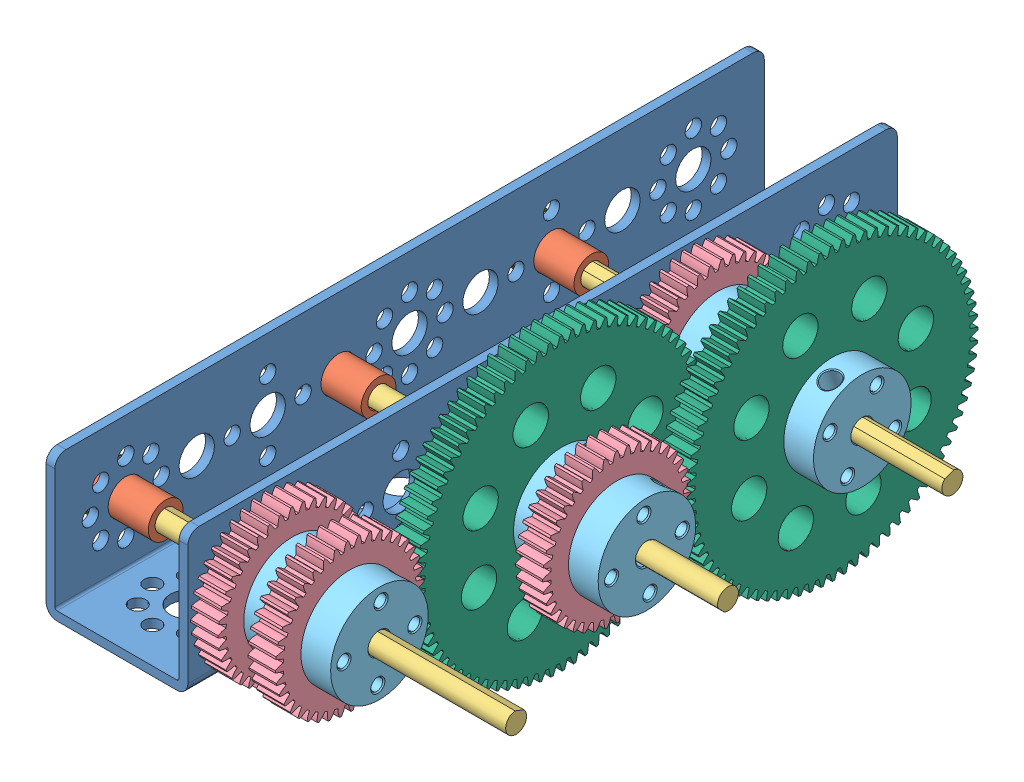
SolidWorks assembly Assem1, configuration Default. Lengths in mm.
Overall size (102.61 86.78 162.15).
25 component instances, 7 part files, 49 mates.
Components (placement in the parent):
- Channel 160mm-1: Channel 160mm [Default] at (26.3428 72.2458 137.2019) size (32 32 160)
- Axle bronze bushing-1: Axle bronze bushing [Default] at (43.7428 88.2458 201.2019) x (0 -0.917806 -0.397029) z (1 0 0) size (11 11 12.4)
- Axle bronze bushing-2: Axle bronze bushing [Default] at (8.9428 88.2458 201.2019) x (0 -0.94918 0.314732) z (-1 0 0) size (11 11 12.4)
- Axle D-shaft-1: Axle D-shaft [Default] at (50.3707 88.2458 201.2019) x (0 -0.370193 -0.928955) z (1 0 0) size (4.73 4.46 100)
- Gear Metric 40T-1: Gear Metric 40T [PreviewCfg] at (43.7428 88.2458 201.2019) x (1 0 0) z (0 -0.086492 0.996253) size (6.2 33.53 33.53)
- Hub axle shaft-1: Hub axle shaft [Default] at (49.9428 88.2458 201.2019) x (0 -0.086492 0.996253) z (-1 0 0) size (22 22 9.5)
- Hub axle shaft-2: Hub axle shaft [Default] at (62.8428 88.2458 201.2019) x (0 0.046409 0.998923) z (-1 0 0) size (22 22 9.5)
- Gear Metric 40T-2: Gear Metric 40T [PreviewCfg] at (56.6428 88.2458 201.2019) x (1 0 0) z (0 0.046409 0.998923) size (6.2 33.53 33.53)
- Gear Metric 80T-1: Gear Metric 80T [Metric - Spur gear 0.8M 80T 20PA 6.2FW ---S80N75H50L8.0N] at (69.5428 88.2458 105.2019) x (1 0 0) z (0 -0.91095 0.412516) size (6.2 65.57 65.57)
- Hub axle shaft-3: Hub axle shaft [Default] at (75.7428 88.2458 105.2019) x (0 -0.91095 0.412516) z (-1 0 0) size (22 22 9.5)
- Axle D-shaft-2: Axle D-shaft [Default] at (50.1599 88.2458 153.2019) x (0 0.722846 0.691009) z (1 0 0) size (4.73 4.46 100)
- Axle bronze bushing-3: Axle bronze bushing [Default] at (8.9428 88.2458 153.2019) x (0 0.924225 0.381849) z (-1 0 0) size (11 11 12.4)
- Axle bronze bushing-4: Axle bronze bushing [Default] at (43.7428 88.2458 153.2019) x (0 0 -1) z (1 0 0) size (11 11 12.4)
- Gear Metric 40T-4: Gear Metric 40T [PreviewCfg] at (43.7428 88.2458 105.2019) x (1 0 0) z (0 0.991285 -0.131734) size (6.2 33.53 33.53)
- Hub axle shaft-4: Hub axle shaft [Default] at (49.9428 88.2458 105.2019) x (0 0.991285 -0.131734) z (-1 0 0) size (22 22 9.5)
- Axle bronze bushing-5: Axle bronze bushing [Default] at (8.9428 88.2458 105.2019) x (0 0.940822 0.338902) z (-1 0 0) size (11 11 12.4)
- Axle bronze bushing-6: Axle bronze bushing [Default] at (43.7428 88.2458 105.2019) x (0 0 -1) z (1 0 0) size (11 11 12.4)
- Axle D-shaft-3: Axle D-shaft [Default] at (52.7684 88.2458 105.2019) x (0 -0.33568 0.941976) z (-1 0 0) size (4.73 4.46 100)
- Gear Metric 80T-2: Gear Metric 80T [Metric - Spur gear 0.8M 80T 20PA 6.2FW ---S80N75H50L8.0N] at (56.5747 88.2458 153.2019) x (1 0 0) z (0 -0.353673 0.935369) size (6.2 65.57 65.57)
- Hub axle shaft-5: Hub axle shaft [Default] at (62.7747 88.2458 153.2019) x (0 -0.353673 0.935369) z (-1 0 0) size (22 22 9.5)
- Hub axle shaft-6: Hub axle shaft [Default] at (75.6747 88.3466 153.7028) x (0 -0.086492 0.996253) z (-1 0 0) size (22 22 9.5)
- Gear Metric 40T-5: Gear Metric 40T [PreviewCfg] at (69.4747 88.3466 153.7028) x (1 0 0) z (0 -0.086492 0.996253) size (6.2 33.53 33.53)
- 39092_txm-axlesetcollars.step-1: 39092_txm-axlesetcollars.step [Default] at (6.0645 87.8505 105.0147) x (0 0 -1) z (1 0 0) size (11.66 11 6.2)
- 39092_txm-axlesetcollars.step-2: 39092_txm-axlesetcollars.step [Default] at (3.456 87.8564 153.401) x (0 -0.79241 -0.609989) z (1 0 0) size (11.66 11 6.2)
- 39092_txm-axlesetcollars.step-3: 39092_txm-axlesetcollars.step [Default] at (6.039 87.8505 201.0147) x (0 0 -1) z (1 0 0) size (11.66 11 6.2)
Mates (geometry in assembly coordinates):
- Concentric1: concentric: cylinder of Channel 160mm-1 through (42.3428 88.2458 201.2019) axis (-1 0 0) radius 4; cylinder of Axle bronze bushing-1 through (31.3428 88.2458 201.2019) axis (1 0 0) radius 3.925
- Coincident1: coincident: plane of Channel 160mm-1 through (42.3428 74.7458 217.2019) normal (1 0 0); plane of Axle bronze bushing-1 through (42.3428 88.2458 201.2019) normal (-1 0 0)
- Concentric2: concentric: cylinder of Channel 160mm-1 through (42.3428 88.2458 201.2019) axis (-1 0 0) radius 4; cylinder of Axle bronze bushing-2 through (21.3428 88.2458 201.2019) axis (-1 0 0) radius 3.925
- Coincident2: coincident: plane of Channel 160mm-1 through (10.3428 104.2458 217.2019) normal (-1 0 0); plane of Axle bronze bushing-2 through (10.3428 88.2458 201.2019) normal (1 0 0)
- Concentric3: concentric: cylinder of Axle bronze bushing-2 through (21.3428 88.2458 201.2019) axis (-1 0 0) radius 2.4; cylinder of Axle D-shaft-1 through (0.3707 88.2458 201.2019) axis (1 0 0) radius 2.365
- Coincident3: coincident: plane of Gear Metric 40T-1 through (49.9428 88.2458 201.2019) normal (1 0 0); plane of Hub axle shaft-1 through (49.9428 88.2458 201.2019) normal (-1 0 0)
- Concentric4: concentric: cylinder of Gear Metric 40T-1 through (49.9428 96.2158 201.8938) axis (1 0 0) radius 1.75; cylinder of Hub axle shaft-1 through (49.9428 96.2158 201.8938) axis (-1 0 0) radius 1.3526
- Concentric5: concentric: cylinder of Gear Metric 40T-1 through (93.7429 88.2458 201.2019) axis (-1 0 0) radius 4; cylinder of Hub axle shaft-1 through (56.6428 88.2458 201.2019) axis (-1 0 0) radius 2.3495
- Concentric6: concentric: cylinder of Axle D-shaft-1 through (0.3707 88.2458 201.2019) axis (1 0 0) radius 2.365; cylinder of Hub axle shaft-1 through (56.6428 88.2458 201.2019) axis (-1 0 0) radius 2.3495
- Concentric7: concentric: cylinder of Hub axle shaft-2 through (69.5428 88.2458 201.2019) axis (-1 0 0) radius 2.3495; cylinder of Gear Metric 40T-2 through (106.6429 88.2458 201.2019) axis (-1 0 0) radius 4
- Concentric8: concentric: cylinder of Hub axle shaft-2 through (62.8428 96.2372 200.8306) axis (-1 0 0) radius 1.3526; cylinder of Gear Metric 40T-2 through (62.8428 96.2372 200.8306) axis (1 0 0) radius 1.75
- Coincident4: coincident: plane of Hub axle shaft-2 through (62.8428 88.2458 201.2019) normal (-1 0 0); plane of Gear Metric 40T-2 through (62.8428 88.2458 201.2019) normal (1 0 0)
- Concentric9: concentric: cylinder of Axle D-shaft-1 through (0.3707 88.2458 201.2019) axis (1 0 0) radius 2.365; cylinder of Hub axle shaft-2 through (69.5428 88.2458 201.2019) axis (-1 0 0) radius 2.3495
- Coincident5: coincident: plane of Hub axle shaft-1 through (56.6428 88.2458 201.2019) normal (1 0 0); plane of Gear Metric 40T-2 through (56.6428 88.2458 201.2019) normal (-1 0 0)
- Coincident6: coincident: plane of Axle bronze bushing-1 through (43.7428 88.2458 201.2019) normal (1 0 0); plane of Gear Metric 40T-1 through (43.7428 88.2458 201.2019) normal (-1 0 0)
- Concentric10: concentric: cylinder of Gear Metric 80T-1 through (119.5429 88.2458 105.2019) axis (-1 0 0) radius 4; cylinder of Hub axle shaft-3 through (72.9428 88.2458 105.2019) axis (1 0 0) radius 3.9624
- Concentric11: concentric: cylinder of Gear Metric 80T-1 through (69.5428 91.5459 112.4895) axis (1 0 0) radius 1.75; cylinder of Hub axle shaft-3 through (75.7428 91.5459 112.4895) axis (-1 0 0) radius 1.3526
- Coincident7: coincident: plane of Gear Metric 80T-1 through (75.7428 88.2458 105.2019) normal (1 0 0); plane of Hub axle shaft-3 through (75.7428 88.2458 105.2019) normal (-1 0 0)
- Concentric12: concentric: cylinder of Axle D-shaft-2 through (0.1599 88.2458 153.2019) axis (1 0 0) radius 2.365; cylinder of Axle bronze bushing-3 through (21.3428 88.2458 153.2019) axis (-1 0 0) radius 2.4
- Concentric13: concentric: cylinder of Axle D-shaft-2 through (0.1599 88.2458 153.2019) axis (1 0 0) radius 2.365; cylinder of Axle bronze bushing-4 through (31.3428 88.2458 153.2019) axis (1 0 0) radius 2.4
- Concentric14: concentric: cylinder of Channel 160mm-1 through (42.3428 88.2458 153.2019) axis (-1 0 0) radius 4; cylinder of Axle D-shaft-2 through (0.1599 88.2458 153.2019) axis (1 0 0) radius 2.365
- Coincident8: coincident: plane of Channel 160mm-1 through (10.3428 104.2458 217.2019) normal (-1 0 0); plane of Axle bronze bushing-3 through (10.3428 88.2458 153.2019) normal (1 0 0)
- Coincident9: coincident: plane of Channel 160mm-1 through (42.3428 74.7458 217.2019) normal (1 0 0); plane of Axle bronze bushing-4 through (42.3428 88.2458 153.2019) normal (-1 0 0)
- Concentric17: concentric: cylinder of Gear Metric 40T-4 through (93.7429 88.2458 105.2019) axis (-1 0 0) radius 4; cylinder of Hub axle shaft-4 through (56.6428 88.2458 105.2019) axis (-1 0 0) radius 2.3495
- Concentric18: concentric: cylinder of Gear Metric 40T-4 through (49.9428 87.1919 97.2716) axis (1 0 0) radius 1.75; cylinder of Hub axle shaft-4 through (49.9428 87.1919 97.2716) axis (-1 0 0) radius 1.3526
- Coincident10: coincident: plane of Gear Metric 40T-4 through (49.9428 88.2458 105.2019) normal (1 0 0); plane of Hub axle shaft-4 through (49.9428 88.2458 105.2019) normal (-1 0 0)
- Concentric20: concentric: cylinder of Axle bronze bushing-5 through (21.3428 88.2458 105.2019) axis (-1 0 0) radius 2.4; cylinder of Axle D-shaft-3 through (102.7684 88.2458 105.2019) axis (-1 0 0) radius 2.365
- Concentric21: concentric: cylinder of Axle bronze bushing-6 through (31.3428 88.2458 105.2019) axis (1 0 0) radius 2.4; cylinder of Axle D-shaft-3 through (102.7684 88.2458 105.2019) axis (-1 0 0) radius 2.365
- Concentric22: concentric: cylinder of Channel 160mm-1 through (42.3428 88.2458 105.2019) axis (-1 0 0) radius 4; cylinder of Axle bronze bushing-5 through (21.3428 88.2458 105.2019) axis (-1 0 0) radius 3.925
- Coincident12: coincident: plane of Channel 160mm-1 through (42.3428 74.7458 217.2019) normal (1 0 0); plane of Axle bronze bushing-6 through (42.3428 88.2458 105.2019) normal (-1 0 0)
- Coincident13: coincident: plane of Channel 160mm-1 through (10.3428 104.2458 217.2019) normal (-1 0 0); plane of Axle bronze bushing-5 through (10.3428 88.2458 105.2019) normal (1 0 0)
- Coincident14: coincident: plane of Hub axle shaft-5 through (69.4747 88.2458 153.2019) normal (1 0 0); plane of Gear Metric 40T-5 through (69.4747 88.3466 153.7028) normal (-1 0 0)
- Concentric23: concentric: cylinder of Gear Metric 80T-2 through (56.5747 95.7288 156.0313) axis (1 0 0) radius 1.75; cylinder of Hub axle shaft-5 through (62.7747 95.7288 156.0313) axis (-1 0 0) radius 1.3526
- Concentric24: concentric: cylinder of Hub axle shaft-6 through (75.6747 96.3167 154.3947) axis (-1 0 0) radius 1.3526; cylinder of Gear Metric 40T-5 through (75.6747 96.3167 154.3947) axis (1 0 0) radius 1.75
- Concentric25: concentric: cylinder of Gear Metric 80T-2 through (106.5747 88.2458 153.2019) axis (-1 0 0) radius 4; cylinder of Hub axle shaft-5 through (59.9747 88.2458 153.2019) axis (1 0 0) radius 3.9624
- Concentric26: concentric: cylinder of Hub axle shaft-6 through (82.3747 88.3466 153.7028) axis (-1 0 0) radius 2.3495; cylinder of Gear Metric 40T-5 through (119.4747 88.3466 153.7028) axis (-1 0 0) radius 4
- Coincident15: coincident: plane of Hub axle shaft-6 through (75.6747 88.3466 153.7028) normal (-1 0 0); plane of Gear Metric 40T-5 through (75.6747 88.3466 153.7028) normal (1 0 0)
- Coincident16: coincident: plane of Gear Metric 80T-2 through (62.7747 88.2458 153.2019) normal (1 0 0); plane of Hub axle shaft-5 through (62.7747 88.2458 153.2019) normal (-1 0 0)
- Concentric27: concentric: cylinder of Hub axle shaft-3 through (82.4428 88.2458 105.2019) axis (-1 0 0) radius 2.3495; cylinder of Axle D-shaft-3 through (102.7684 88.2458 105.2019) axis (-1 0 0) radius 2.365
- Concentric28: concentric: cylinder of Hub axle shaft-4 through (56.6428 88.2458 105.2019) axis (-1 0 0) radius 2.3495; cylinder of Axle D-shaft-3 through (102.7684 88.2458 105.2019) axis (-1 0 0) radius 2.365
- Distance1: distance = 56.4148 mm: plane of Axle D-shaft-2 through (0.1599 88.2458 153.2019) normal (-1 0 0); plane of Gear Metric 80T-2 through (56.5747 88.2458 153.2019) normal (-1 0 0)
- Coincident20: coincident: plane of Gear Metric 40T-4 through (43.7428 88.2458 105.2019) normal (-1 0 0); plane of Axle bronze bushing-6 through (43.7428 88.2458 105.2019) normal (1 0 0)
- Coincident21: coincident: plane of Hub axle shaft-2 through (69.5428 88.2458 201.2019) normal (1 0 0); plane of Gear Metric 80T-1 through (69.5428 88.2458 105.2019) normal (-1 0 0)
- Concentric29: concentric: cylinder of Axle D-shaft-3 through (102.7684 88.2458 105.2019) axis (-1 0 0) radius 2.365; cylinder of 39092_txm-axlesetcollars.step-1 through (2.7684 88.2458 105.2019) axis (1 0 0) radius 2.425
- Coincident22: coincident: plane of Axle D-shaft-3 through (2.7684 88.2458 105.2019) normal (-1 0 0); plane of 39092_txm-axlesetcollars.step-1 through (2.7684 88.2458 105.2019) normal (-1 0 0)
- Concentric30: concentric: cylinder of Axle D-shaft-1 through (0.3707 88.2458 201.2019) axis (1 0 0) radius 2.365; cylinder of 39092_txm-axlesetcollars.step-3 through (2.7428 88.2458 201.2019) axis (1 0 0) radius 2.425
- Concentric31: concentric: cylinder of Axle D-shaft-2 through (0.1599 88.2458 153.2019) axis (1 0 0) radius 2.365; cylinder of 39092_txm-axlesetcollars.step-2 through (0.1599 88.2458 153.2019) axis (1 0 0) radius 2.425
- Coincident24: coincident: plane of Axle D-shaft-2 through (0.1599 88.2458 153.2019) normal (-1 0 0); plane of 39092_txm-axlesetcollars.step-2 through (0.1599 88.2458 153.2019) normal (-1 0 0)
- Coincident28: coincident: plane of Axle bronze bushing-2 through (8.9428 88.2458 201.2019) normal (-1 0 0); plane of 39092_txm-axlesetcollars.step-3 through (8.9428 88.2458 201.2019) normal (1 0 0)
